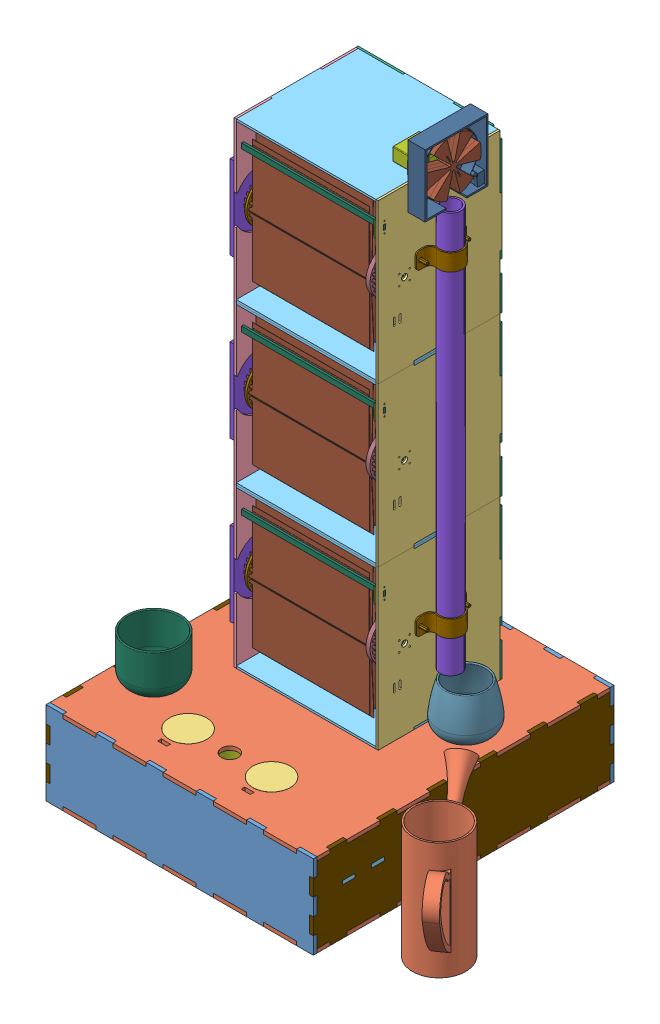
SolidWorks assembly TopLevelAssy_final, configuration Default. Lengths in mm.
Overall size (1478.61 1160.69 1655.18).
164 component instances, 34 part files, 63 mates.
Components (placement in the parent):
- Pot-1: Pot [Default] at (31.4512 127 168.0022) x (0.976936 0 0.213531) z (-0.213531 0 0.976936) size (88.9 76.2 88.9)
- WateringCan-1: WateringCan [Default] at (300.071 0 362.7314) x (-0.576518 0 -0.817085) z (0.817085 0 -0.576518) size (261.08 212.45 184)
- SingleBox-1: SingleBox [Default] at (-1041.1586 1159.5345 1655.1813) size (8.25 0 8.5)
- AllAssembly-v1-stacked-1: AllAssembly-v1-stacked [Default] at (107.7489 434.7752 58.4339) x (0 0 1) z (0 -1 0) size (239.32 247.83 744.86)
  - BasicFlipbook-1: BasicFlipbook [Default] at (-56.8677 536.304 -217.1524) size (239.32 247.83 262.26)
    - sidePanel-bearing-1: sidePanel-bearing [Default] at (77.8088 -538.0926 524.9276) size (188.59 3.17 241.3)
    - sidePanel-spindle-1: sidePanel-spindle [Default] at (77.8088 -322.1926 524.9276) size (188.59 3.17 241.3)
    - topPanel-1: topPanel [Default] at (170.5188 -428.5551 283.6276) x (0 -1 0) z (0 0 1) size (219.07 188.59 3.17)
    - topPanel-2: topPanel [Default] at (170.5188 -428.5551 521.7526) x (0 -1 0) z (0 0 1) size (219.07 188.59 3.17)
    - backPanel-1: backPanel [Default] at (77.8088 -538.0926 524.9276) x (0 1 0) z (0 0 1) size (219.07 3.17 241.3)
    - servo-1: servo [Default] at (213.1908 -290.2676 404.2776) x (1 0 0) z (0 -1 0) size (52.83 20.07 43.1)
    - sidePanel-motor-1: sidePanel-motor [Default] at (77.8088 -319.0176 524.9276) size (101.6 6.35 127)
    - FlipHubAssy_11_14_16-2: FlipHubAssy_11_14_16 [Default] at (223.2238 -424.2676 404.2776) x (0 1 0) z (0.343761 0 0.939057) size (212.25 171.9 216.35) (flexible)
      - Hub_11_16_16v1-3: Hub_11_16_16v1 [Kerf Removed] at (92.075 0 0) x (0 -0.836215 0.548402) z (1 0 0) size (67.6 67.6 3.17)
      - 4mmShaft-1: 4mmShaft [Default] at (-110.65 0 0) x (0 0.397838 0.917456) z (1 0 0) size (4 4 201.85)
      - flipcard-2: flipcard [Default] at (101.6 -15.2897 -21.654) x (-1 0 0) z (0 0.118273 0.992981) size (203.2 0.36 88.9)
      - flipcard-3: flipcard [Default] at (101.6 -20.7049 -16.8264) x (-1 0 0) z (0 0.229727 0.973255) size (203.2 0.36 88.9)
      - flipcard-4: flipcard [Default] at (101.6 -24.7798 -10.679) x (-1 0 0) z (0 0.290896 0.956755) size (203.2 0.36 88.9)
      - flipcard-5: flipcard [Default] at (101.6 -27.1726 -3.6323) x (-1 0 0) z (0 0.324243 0.945974) size (203.2 0.36 88.9)
      - flipcard-6: flipcard [Default] at (101.6 -27.6554 3.8125) x (-1 0 0) z (0 0.355007 0.934864) size (203.2 0.36 88.9)
      - flipcard-7: flipcard [Default] at (101.6 6.9617 25.991) x (-1 0 0) z (0 -0.804275 -0.594258) size (203.2 0.36 88.9)
      - flipcard-8: flipcard [Default] at (101.6 13.6608 22.8217) x (-1 0 0) z (0 -0.829103 -0.559096) size (203.2 0.36 88.9)
      - flipcard-9: flipcard [Default] at (101.6 12.4258 -23.2935) x (-1 0 0) z (0 -0.27854 0.960425) size (203.2 0.36 88.9)
      - flipcard-10: flipcard [Default] at (101.6 19.1668 18.301) x (-1 0 0) z (0 -0.912348 -0.409415) size (203.2 0.36 88.9)
      - flipcard-11: flipcard [Default] at (101.6 25.8239 6.5692) x (-1 0 0) z (0 -0.973268 0.229671) size (203.2 0.36 88.9)
      - flipcard-12: flipcard [Default] at (101.6 -7.402 26.2839) x (-1 0 0) z (0 -0.588891 -0.808212) size (203.2 0.36 88.9)
      - flipcard-13: flipcard [Default] at (101.6 23.2571 13.1974) x (-1 0 0) z (0 -0.999195 0.040112) size (203.2 0.36 88.9)
      - flipcard-14: flipcard [Default] at (101.6 -0.029 26.9321) x (-1 0 0) z (0 -0.634806 -0.772672) size (203.2 0.36 88.9)
      - flipcard-15: flipcard [Default] at (101.6 -14.3329 23.6973) x (-1 0 0) z (0 -0.524162 -0.851618) size (203.2 0.36 88.9)
      - flipcard-16: flipcard [Default] at (101.6 25.5857 -7.2828) x (-1 0 0) z (0 -0.75236 0.658752) size (203.2 0.36 88.9)
      - flipcard-17: flipcard [Default] at (101.6 -20.2143 19.2851) x (-1 0 0) z (0 -0.387069 -0.922051) size (203.2 0.36 88.9)
      - flipcard-18: flipcard [Default] at (101.6 -26.2822 11.1902) x (-1 0 0) z (0 0.343761 0.939057) size (203.2 0.36 88.9)
      - flipcard-19: flipcard [Default] at (101.6 26.6468 -0.3343) x (-1 0 0) z (0 -0.879712 0.475507) size (203.2 0.36 88.9)
      - flipcard-20: flipcard [Default] at (101.6 -25.0081 13.5575) x (-1 0 0) z (0 -0.343761 -0.939057) size (203.2 0.36 88.9)
      - flipcard-21: flipcard [Default] at (101.6 22.7931 -13.6775) x (-1 0 0) z (0 -0.570443 0.821337) size (203.2 0.36 88.9)
      - flipcard-22: flipcard [Default] at (101.6 5.6236 -25.7226) x (-1 0 0) z (0 -0.165302 0.986243) size (203.2 0.36 88.9)
      - flipcard-23: flipcard [Default] at (101.6 -1.5593 -26.2681) x (-1 0 0) z (0 -0.043757 0.999042) size (203.2 0.36 88.9)
      - flipcard-24: flipcard [Default] at (101.6 18.5239 -19.098) x (-1 0 0) z (0 -0.319136 0.947709) size (203.2 0.36 88.9)
      - flipcard-26: flipcard [Default] at (101.6 -8.628 -24.8962) x (-1 0 0) z (0 0.08016 0.996782) size (203.2 0.36 88.9)
      - CenterSupport-2: CenterSupport [After Cut Kerf Removed] at (0 3.7916 3.0025) x (1 0 0) z (0 -0.836215 0.548402) size (190.5 19.05 3.05)
      - CenterSupport-3: CenterSupport [After Cut Kerf Removed] at (0 -3.0025 3.7916) x (1 0 0) z (0 -0.548402 -0.836215) size (190.5 19.05 3.05)
      - CenterSupport-4: CenterSupport [After Cut Kerf Removed] at (0 -3.7916 -3.0025) x (1 0 0) z (0 0.836215 -0.548402) size (190.5 19.05 3.05)
      - CenterSupport-5: CenterSupport [After Cut Kerf Removed] at (0 3.0025 -3.7916) x (1 0 0) z (0 0.548402 0.836215) size (190.5 19.05 3.05)
      - Hub_11_16_16v1-thicker-3: Hub_11_16_16v1-thicker [Kerf Removed] at (-95.25 0 0) x (0 -0.548402 -0.836215) z (1 0 0) size (67.6 72.68 6.35)
      - bearingSleeve-nut-1: bearingSleeve-nut [Default] at (-109.05 0 0) x (0 -0.939057 0.343761) z (-1 0 0) size (25.4 25.4 6.95)
    - stopper-2: stopper [Default] at (255.3548 -538.0926 327.0616) x (0 1 0) z (-1 0 0) size (219.07 7.87 3.3)
    - stopperSupport-1: stopperSupport [Default] at (243.9268 -531.9176 311.1876) x (1 0 0) z (0 -1 0) size (19.3 23.87 3)
    - switchSupport-1: switchSupport [Default] at (224.5478 -534.9176 453.6616) x (1 0 0) z (0 1 0) size (19.84 9.4 12.7)
  - BasicFlipbook-2: BasicFlipbook [Default] at (-56.8677 536.304 -458.4524) size (239.32 247.83 262.26)
    - sidePanel-bearing-1: sidePanel-bearing [Default] at (77.8088 -538.0926 524.9276) size (188.59 3.17 241.3)
    - sidePanel-spindle-1: sidePanel-spindle [Default] at (77.8088 -322.1926 524.9276) size (188.59 3.17 241.3)
    - topPanel-1: topPanel [Default] at (170.5188 -428.5551 283.6276) x (0 -1 0) z (0 0 1) size (219.07 188.59 3.17)
    - topPanel-2: topPanel [Default] at (170.5188 -428.5551 521.7526) x (0 -1 0) z (0 0 1) size (219.07 188.59 3.17)
    - backPanel-1: backPanel [Default] at (77.8088 -538.0926 524.9276) x (0 1 0) z (0 0 1) size (219.07 3.17 241.3)
    - servo-1: servo [Default] at (213.1908 -290.2676 404.2776) x (1 0 0) z (0 -1 0) size (52.83 20.07 43.1)
    - sidePanel-motor-1: sidePanel-motor [Default] at (77.8088 -319.0176 524.9276) size (101.6 6.35 127)
    - FlipHubAssy_11_14_16-2: FlipHubAssy_11_14_16 [Default] at (223.2238 -424.2676 404.2776) x (0 1 0) z (0.343761 0 0.939057) size (212.25 171.9 216.35) (flexible)
      - Hub_11_16_16v1-3: Hub_11_16_16v1 [Kerf Removed] at (92.075 0 0) x (0 -0.836215 0.548402) z (1 0 0) size (67.6 67.6 3.17)
      - 4mmShaft-1: 4mmShaft [Default] at (-110.65 0 0) x (0 0.397838 0.917456) z (1 0 0) size (4 4 201.85)
      - flipcard-2: flipcard [Default] at (101.6 -15.2897 -21.654) x (-1 0 0) z (0 0.118273 0.992981) size (203.2 0.36 88.9)
      - flipcard-3: flipcard [Default] at (101.6 -20.7049 -16.8264) x (-1 0 0) z (0 0.229727 0.973255) size (203.2 0.36 88.9)
      - flipcard-4: flipcard [Default] at (101.6 -24.7798 -10.679) x (-1 0 0) z (0 0.290896 0.956755) size (203.2 0.36 88.9)
      - flipcard-5: flipcard [Default] at (101.6 -27.1726 -3.6323) x (-1 0 0) z (0 0.324243 0.945974) size (203.2 0.36 88.9)
      - flipcard-6: flipcard [Default] at (101.6 -27.6554 3.8125) x (-1 0 0) z (0 0.355007 0.934864) size (203.2 0.36 88.9)
      - flipcard-7: flipcard [Default] at (101.6 6.9617 25.991) x (-1 0 0) z (0 -0.804275 -0.594258) size (203.2 0.36 88.9)
      - flipcard-8: flipcard [Default] at (101.6 13.6608 22.8217) x (-1 0 0) z (0 -0.829103 -0.559096) size (203.2 0.36 88.9)
      - flipcard-9: flipcard [Default] at (101.6 12.4258 -23.2935) x (-1 0 0) z (0 -0.27854 0.960425) size (203.2 0.36 88.9)
      - flipcard-10: flipcard [Default] at (101.6 19.1668 18.301) x (-1 0 0) z (0 -0.912348 -0.409415) size (203.2 0.36 88.9)
      - flipcard-11: flipcard [Default] at (101.6 25.8239 6.5692) x (-1 0 0) z (0 -0.973268 0.229671) size (203.2 0.36 88.9)
      - flipcard-12: flipcard [Default] at (101.6 -7.402 26.2839) x (-1 0 0) z (0 -0.588891 -0.808212) size (203.2 0.36 88.9)
      - flipcard-13: flipcard [Default] at (101.6 23.2571 13.1974) x (-1 0 0) z (0 -0.999195 0.040112) size (203.2 0.36 88.9)
      - flipcard-14: flipcard [Default] at (101.6 -0.029 26.9321) x (-1 0 0) z (0 -0.634806 -0.772672) size (203.2 0.36 88.9)
      - flipcard-15: flipcard [Default] at (101.6 -14.3329 23.6973) x (-1 0 0) z (0 -0.524162 -0.851618) size (203.2 0.36 88.9)
      - flipcard-16: flipcard [Default] at (101.6 25.5857 -7.2828) x (-1 0 0) z (0 -0.75236 0.658752) size (203.2 0.36 88.9)
      - flipcard-17: flipcard [Default] at (101.6 -20.2143 19.2851) x (-1 0 0) z (0 -0.387069 -0.922051) size (203.2 0.36 88.9)
      - flipcard-18: flipcard [Default] at (101.6 -26.2822 11.1902) x (-1 0 0) z (0 0.343761 0.939057) size (203.2 0.36 88.9)
      - flipcard-19: flipcard [Default] at (101.6 26.6468 -0.3343) x (-1 0 0) z (0 -0.879712 0.475507) size (203.2 0.36 88.9)
      - flipcard-20: flipcard [Default] at (101.6 -25.0081 13.5575) x (-1 0 0) z (0 -0.343761 -0.939057) size (203.2 0.36 88.9)
      - flipcard-21: flipcard [Default] at (101.6 22.7931 -13.6775) x (-1 0 0) z (0 -0.570443 0.821337) size (203.2 0.36 88.9)
      - flipcard-22: flipcard [Default] at (101.6 5.6236 -25.7226) x (-1 0 0) z (0 -0.165302 0.986243) size (203.2 0.36 88.9)
      - flipcard-23: flipcard [Default] at (101.6 -1.5593 -26.2681) x (-1 0 0) z (0 -0.043757 0.999042) size (203.2 0.36 88.9)
      - flipcard-24: flipcard [Default] at (101.6 18.5239 -19.098) x (-1 0 0) z (0 -0.319136 0.947709) size (203.2 0.36 88.9)
      - flipcard-26: flipcard [Default] at (101.6 -8.628 -24.8962) x (-1 0 0) z (0 0.08016 0.996782) size (203.2 0.36 88.9)
      - CenterSupport-2: CenterSupport [After Cut Kerf Removed] at (0 3.7916 3.0025) x (1 0 0) z (0 -0.836215 0.548402) size (190.5 19.05 3.05)
      - CenterSupport-3: CenterSupport [After Cut Kerf Removed] at (0 -3.0025 3.7916) x (1 0 0) z (0 -0.548402 -0.836215) size (190.5 19.05 3.05)
      - CenterSupport-4: CenterSupport [After Cut Kerf Removed] at (0 -3.7916 -3.0025) x (1 0 0) z (0 0.836215 -0.548402) size (190.5 19.05 3.05)
      - CenterSupport-5: CenterSupport [After Cut Kerf Removed] at (0 3.0025 -3.7916) x (1 0 0) z (0 0.548402 0.836215) size (190.5 19.05 3.05)
      - Hub_11_16_16v1-thicker-3: Hub_11_16_16v1-thicker [Kerf Removed] at (-95.25 0 0) x (0 -0.548402 -0.836215) z (1 0 0) size (67.6 72.68 6.35)
      - bearingSleeve-nut-1: bearingSleeve-nut [Default] at (-109.05 0 0) x (0 -0.939057 0.343761) z (-1 0 0) size (25.4 25.4 6.95)
    - stopper-2: stopper [Default] at (255.3548 -538.0926 327.0616) x (0 1 0) z (-1 0 0) size (219.07 7.87 3.3)
    - stopperSupport-1: stopperSupport [Default] at (243.9268 -531.9176 311.1876) x (1 0 0) z (0 -1 0) size (19.3 23.87 3)
    - switchSupport-1: switchSupport [Default] at (224.5478 -534.9176 453.6616) x (1 0 0) z (0 1 0) size (19.84 9.4 12.7)
  - BasicFlipbook-3: BasicFlipbook [Default] at (-56.8677 536.304 -699.7524) size (239.32 247.83 262.26)
    - sidePanel-bearing-1: sidePanel-bearing [Default] at (77.8088 -538.0926 524.9276) size (188.59 3.17 241.3)
    - sidePanel-spindle-1: sidePanel-spindle [Default] at (77.8088 -322.1926 524.9276) size (188.59 3.17 241.3)
    - topPanel-1: topPanel [Default] at (170.5188 -428.5551 283.6276) x (0 -1 0) z (0 0 1) size (219.07 188.59 3.17)
    - topPanel-2: topPanel [Default] at (170.5188 -428.5551 521.7526) x (0 -1 0) z (0 0 1) size (219.07 188.59 3.17)
    - backPanel-1: backPanel [Default] at (77.8088 -538.0926 524.9276) x (0 1 0) z (0 0 1) size (219.07 3.17 241.3)
    - servo-1: servo [Default] at (213.1908 -290.2676 404.2776) x (1 0 0) z (0 -1 0) size (52.83 20.07 43.1)
    - sidePanel-motor-1: sidePanel-motor [Default] at (77.8088 -319.0176 524.9276) size (101.6 6.35 127)
    - FlipHubAssy_11_14_16-2: FlipHubAssy_11_14_16 [Default] at (223.2238 -424.2676 404.2776) x (0 1 0) z (0.343761 0 0.939057) size (212.25 171.9 216.35) (flexible)
      - Hub_11_16_16v1-3: Hub_11_16_16v1 [Kerf Removed] at (92.075 0 0) x (0 -0.836215 0.548402) z (1 0 0) size (67.6 67.6 3.17)
      - 4mmShaft-1: 4mmShaft [Default] at (-110.65 0 0) x (0 0.397838 0.917456) z (1 0 0) size (4 4 201.85)
      - flipcard-2: flipcard [Default] at (101.6 -15.2897 -21.654) x (-1 0 0) z (0 0.118273 0.992981) size (203.2 0.36 88.9)
      - flipcard-3: flipcard [Default] at (101.6 -20.7049 -16.8264) x (-1 0 0) z (0 0.229727 0.973255) size (203.2 0.36 88.9)
      - flipcard-4: flipcard [Default] at (101.6 -24.7798 -10.679) x (-1 0 0) z (0 0.290896 0.956755) size (203.2 0.36 88.9)
      - flipcard-5: flipcard [Default] at (101.6 -27.1726 -3.6323) x (-1 0 0) z (0 0.324243 0.945974) size (203.2 0.36 88.9)
      - flipcard-6: flipcard [Default] at (101.6 -27.6554 3.8125) x (-1 0 0) z (0 0.355007 0.934864) size (203.2 0.36 88.9)
      - flipcard-7: flipcard [Default] at (101.6 6.9617 25.991) x (-1 0 0) z (0 -0.804275 -0.594258) size (203.2 0.36 88.9)
      - flipcard-8: flipcard [Default] at (101.6 13.6608 22.8217) x (-1 0 0) z (0 -0.829103 -0.559096) size (203.2 0.36 88.9)
      - flipcard-9: flipcard [Default] at (101.6 12.4258 -23.2935) x (-1 0 0) z (0 -0.27854 0.960425) size (203.2 0.36 88.9)
      - flipcard-10: flipcard [Default] at (101.6 19.1668 18.301) x (-1 0 0) z (0 -0.912348 -0.409415) size (203.2 0.36 88.9)
      - flipcard-11: flipcard [Default] at (101.6 25.8239 6.5692) x (-1 0 0) z (0 -0.973268 0.229671) size (203.2 0.36 88.9)
      - flipcard-12: flipcard [Default] at (101.6 -7.402 26.2839) x (-1 0 0) z (0 -0.588891 -0.808212) size (203.2 0.36 88.9)
      - flipcard-13: flipcard [Default] at (101.6 23.2571 13.1974) x (-1 0 0) z (0 -0.999195 0.040112) size (203.2 0.36 88.9)
      - flipcard-14: flipcard [Default] at (101.6 -0.029 26.9321) x (-1 0 0) z (0 -0.634806 -0.772672) size (203.2 0.36 88.9)
      - flipcard-15: flipcard [Default] at (101.6 -14.3329 23.6973) x (-1 0 0) z (0 -0.524162 -0.851618) size (203.2 0.36 88.9)
      - flipcard-16: flipcard [Default] at (101.6 25.5857 -7.2828) x (-1 0 0) z (0 -0.75236 0.658752) size (203.2 0.36 88.9)
      - flipcard-17: flipcard [Default] at (101.6 -20.2143 19.2851) x (-1 0 0) z (0 -0.387069 -0.922051) size (203.2 0.36 88.9)
      - flipcard-18: flipcard [Default] at (101.6 -26.2822 11.1902) x (-1 0 0) z (0 0.343761 0.939057) size (203.2 0.36 88.9)
      - flipcard-19: flipcard [Default] at (101.6 26.6468 -0.3343) x (-1 0 0) z (0 -0.879712 0.475507) size (203.2 0.36 88.9)
      - flipcard-20: flipcard [Default] at (101.6 -25.0081 13.5575) x (-1 0 0) z (0 -0.343761 -0.939057) size (203.2 0.36 88.9)
      - flipcard-21: flipcard [Default] at (101.6 22.7931 -13.6775) x (-1 0 0) z (0 -0.570443 0.821337) size (203.2 0.36 88.9)
      - flipcard-22: flipcard [Default] at (101.6 5.6236 -25.7226) x (-1 0 0) z (0 -0.165302 0.986243) size (203.2 0.36 88.9)
      - flipcard-23: flipcard [Default] at (101.6 -1.5593 -26.2681) x (-1 0 0) z (0 -0.043757 0.999042) size (203.2 0.36 88.9)
      - flipcard-24: flipcard [Default] at (101.6 18.5239 -19.098) x (-1 0 0) z (0 -0.319136 0.947709) size (203.2 0.36 88.9)
      - flipcard-26: flipcard [Default] at (101.6 -8.628 -24.8962) x (-1 0 0) z (0 0.08016 0.996782) size (203.2 0.36 88.9)
      - CenterSupport-2: CenterSupport [After Cut Kerf Removed] at (0 3.7916 3.0025) x (1 0 0) z (0 -0.836215 0.548402) size (190.5 19.05 3.05)
      - CenterSupport-3: CenterSupport [After Cut Kerf Removed] at (0 -3.0025 3.7916) x (1 0 0) z (0 -0.548402 -0.836215) size (190.5 19.05 3.05)
      - CenterSupport-4: CenterSupport [After Cut Kerf Removed] at (0 -3.7916 -3.0025) x (1 0 0) z (0 0.836215 -0.548402) size (190.5 19.05 3.05)
      - CenterSupport-5: CenterSupport [After Cut Kerf Removed] at (0 3.0025 -3.7916) x (1 0 0) z (0 0.548402 0.836215) size (190.5 19.05 3.05)
      - Hub_11_16_16v1-thicker-3: Hub_11_16_16v1-thicker [Kerf Removed] at (-95.25 0 0) x (0 -0.548402 -0.836215) z (1 0 0) size (67.6 72.68 6.35)
      - bearingSleeve-nut-1: bearingSleeve-nut [Default] at (-109.05 0 0) x (0 -0.939057 0.343761) z (-1 0 0) size (25.4 25.4 6.95)
    - stopper-2: stopper [Default] at (255.3548 -538.0926 327.0616) x (0 1 0) z (-1 0 0) size (219.07 7.87 3.3)
    - stopperSupport-1: stopperSupport [Default] at (243.9268 -531.9176 311.1876) x (1 0 0) z (0 -1 0) size (19.3 23.87 3)
    - switchSupport-1: switchSupport [Default] at (224.5478 -534.9176 453.6616) x (1 0 0) z (0 1 0) size (19.84 9.4 12.7)
- Box_LeftRight-1: Box_LeftRight [Default] at (203.2 63.5 228.6) x (0 0 1) z (-1 0 0) size (457.2 127 5.71)
- Box_LeftRight-2: Box_LeftRight [Left] at (-197.485 63.5 228.6) x (0 0 1) z (-1 0 0) size (457.2 127 5.71)
- Box_FrontBack-2: Box_FrontBack [Back] at (0 63.5 0) size (406.4 127 5.71)
- Box_TopBottom-1: Box_TopBottom [Simple Bottom] at (0 0 228.6) x (1 0 0) z (0 1 0) size (406.4 457.2 5.71)
- Box_FrontBack-1: Box_FrontBack [Front] at (0 63.5 451.485) size (406.4 127 5.71)
- Box_TopBottom-2: Box_TopBottom [Simple Top] at (0 121.285 228.6) x (1 0 0) z (0 1 0) size (406.4 457.2 5.71)
- Box_FrostedHand-1: Box_FrostedHand [Default] at (-63.5 121.3358 381) x (1 0 0) z (0 1 0) size (56.64 56.64 5.71)
- Box_FrostedHand-2: Box_FrostedHand [Default] at (63.5 121.412 381) x (1 0 0) z (0 1 0) size (56.64 56.64 5.71)
- SeedDoor-1: SeedDoor [Default] at (-206.375 26.4984 358.3219) x (0 -0.092883 -0.995677) z (1 0 0) size (50.8 50.8 3.17)
- Box_LED_Sensor Mount-1: Box_LED_Sensor Mount [Default] at (0 70.485 381) x (1 0 0) z (0 1 0) size (406.4 63.5 5.71)
- PowerSupply-1: PowerSupply [Default] at (-124.46 5.715 202.565) x (0 0 -1) z (1 0 0) size (203.2 101.6 133.35)
- SeedLEDShroud-1: SeedLEDShroud [Default] at (63.5 120.65 381) x (1 0 0) z (0 -1 0) size (50.8 50.8 44.45)
- SeedLEDShroud-2: SeedLEDShroud [Default] at (-63.5 120.65 381) x (1 0 0) z (0 -1 0) size (50.8 50.8 44.45)
- SeedLEDShroud-3: SeedLEDShroud [Default] at (0 120.65 381) x (1 0 0) z (0 -1 0) size (50.8 50.8 44.45)
- SeedTube-1: SeedTube [Default] at (125.4125 806.45 170.4975) x (-0.559231 0 -0.829012) z (0 -1 0) size (31.75 31.75 609.6)
- SeedTubeBracket-1: SeedTubeBracket [Default] at (109.5375 247.65 170.4975) x (0 0 1) z (-1 0 0) size (76.2 25.4 33.78)
- SeedTubeBracket-2: SeedTubeBracket [Default] at (109.5375 730.25 170.4975) x (0 0 1) z (-1 0 0) size (76.2 25.4 33.78)
- FruitDispenseAssm-1: FruitDispenseAssm [Default] at (109.5375 860.933 172.085) x (0 0 -1) z (1 0 0) size (95.25 95.25 66.48)
  - servo-1: servo [Default] at (-10.033 0 -40.1) size (52.83 20.07 43.1)
  - FruitDispenseDrum-1: FruitDispenseDrum [Default] x (-1 0 0) z (0 0 -1) size (95.25 95.25 26.38)
- FruitPaddleWheel-2: FruitPaddleWheel [Default] at (131.5875 860.933 172.085) x (0 1 0) z (0 0 1) size (81.32 19.05 83.82)
  - fruitMotorSpindle1-1: fruitMotorSpindle1 [Default] at origin size (81.32 6.35 83.82)
  - fruitMotorSpindle1-2: fruitMotorSpindle1 [Default] at (0 6.35 0) size (81.32 6.35 83.82)
  - fruitMotorSpindle1-3: fruitMotorSpindle1 [Default] at (0 12.7 0) size (81.32 6.35 83.82)
- SeedRamp-1: SeedRamp [Default] at (-197.485 5.715 339.725) x (0 0 1) z (-1 0 0) size (111.76 63.5 254)
- CircuitLayout-1: CircuitLayout [Default] at (-31.115 5.715 393.065) x (1 0 0) z (0 1 0) size (317.5 381 50.8)
- FruitGlass-1: FruitGlass [Default] at (150.8125 127 172.7726) x (-0.420832 0 -0.907138) z (0.907138 0 -0.420832) size (82.55 69.47 82.55)
- SeedGlass-2: SeedGlass [Default] at (-149.8177 127 346.9329) size (82.55 69.9 82.55)
Mates (geometry in assembly coordinates):
- Coincident9: coincident anti-aligned: plane of Box_TopBottom-2 through (0 127 228.6) normal (0 1 0); plane of Pot-1 through (31.4512 127 168.0022) normal (0 -1 0)
- Coincident10: coincident aligned: plane of Box_TopBottom-1 through (0 0 228.6) normal (0 -1 0); plane of WateringCan-1 through (300.071 0 362.7314) normal (0 -1 0)
- Coincident12: coincident: moEndPointRef_w of AllAssembly-v1-stacked-1/BasicFlipbook-1/topPanel-2; plane of assembly
- Coincident14: coincident aligned: plane of Box_TopBottom-1 through (-203.2 5.715 457.2) normal (-1 0 0); plane of Box_TopBottom-2 through (-203.2 127 457.2) normal (-1 0 0)
- Coincident15: coincident aligned: plane of Box_TopBottom-1 through (-203.2 5.715 457.2) normal (0 0 1); plane of Box_TopBottom-2 through (-203.2 127 457.2) normal (0 0 1)
- Coincident18: coincident aligned: plane of Box_TopBottom-1 through (-203.2 5.715 457.2) normal (-1 0 0); plane of Box_LeftRight-2 through (-203.2 63.5 228.6) normal (-1 0 0)
- Coincident21: coincident aligned: plane of Box_TopBottom-2 through (0 127 228.6) normal (0 1 0); plane of Box_LeftRight-1 through (197.485 127 0) normal (0 1 0)
- Coincident22: coincident aligned: plane of Box_TopBottom-2 through (-203.2 127 457.2) normal (0 0 1); plane of Box_FrontBack-1 through (0 63.5 457.2) normal (0 0 1)
- Coincident23: coincident aligned: plane of Box_TopBottom-2 through (-203.2 127 457.2) normal (-1 0 0); plane of Box_FrontBack-1 through (-203.2 0 457.2) normal (-1 0 0)
- Coincident24: coincident aligned: plane of Box_TopBottom-2 through (0 127 228.6) normal (0 1 0); plane of Box_FrontBack-1 through (-203.2 127 457.2) normal (0 1 0)
- Coincident26: coincident aligned: plane of Box_TopBottom-2 through (203.2 127 457.2) normal (1 0 0); plane of Box_FrontBack-2 through (203.2 0 5.715) normal (1 0 0)
- Coincident27: coincident aligned: plane of Box_TopBottom-2 through (0 127 228.6) normal (0 1 0); plane of Box_FrontBack-2 through (-203.2 127 5.715) normal (0 1 0)
- Coincident28: coincident anti-aligned: plane of Box_TopBottom-1 through (0 0 228.6) normal (0 -1 0); plane of assembly through (0 0 0) normal (0 1 0)
- Coincident29: coincident aligned: plane of Box_TopBottom-2; plane of assembly through (0 0 0) normal (1 0 0)
- Coincident30: coincident anti-aligned: plane of Box_TopBottom-1 through (-203.2 5.715 0) normal (0 0 -1); plane of assembly through (0 0 0) normal (0 0 1)
- Coincident58: coincident aligned: plane of Box_LeftRight-2 through (-203.2 127 0) normal (0 1 0); plane of Box_TopBottom-2 through (0 127 228.6) normal (0 1 0)
- Coincident60: coincident aligned: plane of Box_LeftRight-2 through (-203.2 0 457.2) normal (0 0 1); plane of Box_FrontBack-1 through (0 63.5 457.2) normal (0 0 1)
- Distance2: distance = 0.0508 mm aligned: plane of Box_FrostedHand-1 through (-63.5 127.0508 381) normal (0 1 0); plane of Box_TopBottom-2 through (0 127 228.6) normal (0 1 0)
- Distance3: distance = 0.127 mm aligned: plane of Box_FrostedHand-2 through (63.5 127.127 381) normal (0 1 0); plane of Box_TopBottom-2 through (0 127 228.6) normal (0 1 0)
- Concentric3: concentric aligned: cylinder of Box_TopBottom-2 through (-63.5 127 381) axis (0 -1 0) radius 28.321; cylinder of Box_FrostedHand-1 through (-63.5 127.0508 381) axis (0 -1 0) radius 28.321
- Concentric4: concentric aligned: cylinder of Box_TopBottom-2 through (63.5 127 381) axis (0 -1 0) radius 28.321; cylinder of Box_FrostedHand-2 through (63.5 127.127 381) axis (0 -1 0) radius 28.321
- Coincident61: coincident anti-aligned: plane of AllAssembly-v1-stacked-1/BasicFlipbook-1/topPanel-2 through (0 127 172.085) normal (0 -1 0); plane of Box_TopBottom-2 through (0 127 228.6) normal (0 1 0)
- Coincident62: coincident aligned: plane of Box_LeftRight-1 through (203.2 63.5 228.6) normal (1 0 0); plane of Box_TopBottom-2 through (203.2 127 457.2) normal (1 0 0)
- Coincident63: coincident aligned: plane of Box_LeftRight-1 through (197.485 0 457.2) normal (0 0 1); plane of Box_TopBottom-2 through (-203.2 127 457.2) normal (0 0 1)
- Coincident64: coincident aligned: plane of Box_FrontBack-2 through (0 63.5 0) normal (0 0 -1); plane of Box_TopBottom-2 through (-203.2 127 0) normal (0 0 -1)
- Coincident65: coincident anti-aligned: plane of Box_LeftRight-2 through (-197.485 76.2 349.25) normal (0 -1 0); plane of Box_LED_Sensor Mount-1 through (0 76.2 381) normal (0 1 0)
- Coincident66: coincident anti-aligned: plane of Box_LeftRight-2 through (-197.485 76.2 349.25) normal (0 0 1); plane of Box_LED_Sensor Mount-1 through (-203.2 76.2 349.25) normal (0 0 -1)
- Coincident67: coincident aligned: plane of Box_LeftRight-2 through (-203.2 63.5 228.6) normal (-1 0 0); plane of Box_LED_Sensor Mount-1 through (-203.2 76.2 412.75) normal (-1 0 0)
- Coincident68: coincident anti-aligned: plane of Box_TopBottom-1 through (0 5.715 228.6) normal (0 1 0); plane of PowerSupply-1 through (-124.46 5.715 202.565) normal (0 -1 0)
- Distance4: distance = 6.35 mm anti-aligned: plane of PowerSupply-1 through (-191.135 107.315 304.165) normal (-1 0 0); plane of Box_LeftRight-2 through (-197.485 63.5 228.6) normal (1 0 0)
- Coincident70: coincident aligned: plane of Box_TopBottom-1 through (0 0 228.6) normal (0 -1 0); plane of Box_FrontBack-1 through (-203.2 0 457.2) normal (0 -1 0)
- Distance5: distance = 95.25 mm aligned: plane of PowerSupply-1 through (-57.785 107.315 100.965) normal (0 0 -1); plane of Box_TopBottom-1 through (-177.8 5.715 5.715) normal (0 0 -1)
- Coincident78: coincident anti-aligned: plane of Box_LED_Sensor Mount-1 through (0 76.2 381) normal (0 1 0); plane of SeedLEDShroud-1 through (63.5 76.2 381) normal (0 -1 0)
- Concentric5: concentric aligned: circle of Box_LED_Sensor Mount-1; cylinder of SeedLEDShroud-1 through (63.5 76.2 381) axis (0 1 0) radius 25.4
- Coincident79: coincident anti-aligned: plane of Box_LED_Sensor Mount-1 through (0 76.2 381) normal (0 1 0); plane of SeedLEDShroud-2 through (-63.5 76.2 381) normal (0 -1 0)
- Concentric6: concentric anti-aligned: cylinder of Box_LED_Sensor Mount-1 through (-63.5 76.2 381) axis (0 -1 0) radius 2.54; cylinder of SeedLEDShroud-2 through (-63.5 76.2 381) axis (0 1 0) radius 21.59
- Concentric7: concentric anti-aligned: cylinder of Box_LED_Sensor Mount-1 through (0 76.2 381) axis (0 -1 0) radius 12.7; cylinder of SeedLEDShroud-3 through (0 76.2 381) axis (0 1 0) radius 21.59
- Coincident80: coincident anti-aligned: plane of Box_LED_Sensor Mount-1 through (0 76.2 381) normal (0 1 0); plane of SeedLEDShroud-3 through (0 76.2 381) normal (0 -1 0)
- Concentric8: concentric anti-aligned: cylinder of SeedTube-1 through (125.4125 196.85 170.4975) axis (0 1 0) radius 15.875; cylinder of SeedTubeBracket-1 through (125.4125 273.05 170.4975) axis (0 -1 0) radius 15.875
- Concentric9: concentric anti-aligned: cylinder of SeedTube-1 through (125.4125 196.85 170.4975) axis (0 1 0) radius 15.875; cylinder of SeedTubeBracket-2 through (125.4125 755.65 170.4975) axis (0 -1 0) radius 15.875
- Distance6: distance = 50.8 mm aligned: plane of SeedTubeBracket-1 through (119.6975 247.65 195.8975) normal (0 -1 0); plane of SeedTube-1 through (125.4125 196.85 170.4975) normal (0 -1 0)
- Distance7: distance = 50.8 mm aligned: plane of SeedTube-1 through (125.4125 806.45 170.4975) normal (0 1 0); plane of SeedTubeBracket-2 through (119.6975 755.65 195.8975) normal (0 1 0)
- Coincident83: coincident anti-aligned: plane of AllAssembly-v1-stacked-1/BasicFlipbook-3/sidePanel-bearing-1 through (109.5375 609.6 79.375) normal (1 0 0); plane of SeedTubeBracket-2 through (109.5375 755.65 145.0975) normal (-1 0 0)
- Distance9: distance = 76.2 mm aligned: plane of AllAssembly-v1-stacked-1/BasicFlipbook-1/backPanel-1 through (109.5375 127 76.2) normal (0 0 -1); plane of Box_TopBottom-2 through (-203.2 127 0) normal (0 0 -1)
- Coincident85: coincident anti-aligned: plane of Box_TopBottom-2 through (0 127 228.6) normal (0 1 0); plane of FruitGlass-1 through (150.8125 127 172.7726) normal (0 -1 0)
- Coincident86: coincident anti-aligned: plane of AllAssembly-v1-stacked-1/BasicFlipbook-3/sidePanel-bearing-1 through (109.5375 609.6 79.375) normal (1 0 0); plane of SeedTubeBracket-1 through (109.5375 273.05 145.0975) normal (-1 0 0)
- Symmetric1: symmetric aligned: plane of AllAssembly-v1-stacked-1/BasicFlipbook-1/sidePanel-bearing-1 through (106.3625 127 264.795) normal (0 0 1); plane of AllAssembly-v1-stacked-1/BasicFlipbook-1/backPanel-1 through (109.5375 127 76.2) normal (0 0 -1); plane of SeedTubeBracket-1 through (109.5375 247.65 170.4975) normal (0 0 1)
- Distance10: distance = 44.45 mm aligned: plane of AllAssembly-v1-stacked-1/BasicFlipbook-3/topPanel-1 through (0 850.9 172.085) normal (0 1 0); plane of SeedTube-1 through (125.4125 806.45 170.4975) normal (0 1 0)
- Tangent1: tangent: plane of AllAssembly-v1-stacked-1/BasicFlipbook-1/sidePanel-bearing-1 through (109.5375 127 79.375) normal (1 0 0); torus of FruitGlass-1
- Coincident88: coincident anti-aligned: plane of Box_TopBottom-1 through (0 5.715 228.6) normal (0 1 0); plane of CircuitLayout-1 through (-31.115 5.715 393.065) normal (0 -1 0)
- Coincident89: coincident anti-aligned: plane of Box_LeftRight-1 through (197.485 63.5 228.6) normal (-1 0 0); plane of CircuitLayout-1 through (197.485 8.255 393.065) normal (1 0 0)
- Distance12: distance = 6.35 mm aligned: plane of CircuitLayout-1 through (-31.115 8.255 12.065) normal (0 0 -1); plane of Box_LeftRight-1 through (197.485 76.2 5.715) normal (0 0 -1)
- Coincident90: coincident anti-aligned: plane of AllAssembly-v1-stacked-1/BasicFlipbook-3/sidePanel-bearing-1 through (109.5375 609.6 79.375) normal (1 0 0); plane of FruitDispenseAssm-1/FruitDispenseDrum-1 through (109.5375 860.933 172.085) normal (-1 0 0)
- Coincident91: coincident anti-aligned: plane of AllAssembly-v1-stacked-1/BasicFlipbook-3/topPanel-1 through (0 850.9 172.085) normal (0 1 0); plane of FruitDispenseAssm-1/servo-1 through (107.5375 850.9 202.184) normal (0 -1 0)
- Coincident92: coincident: moEndPointRef_w of AllAssembly-v1-stacked-1/BasicFlipbook-3/topPanel-1; plane of FruitDispenseAssm-1 through (109.5375 860.933 172.085) normal (0 0 -1)
- Coincident93: coincident anti-aligned: plane of Box_TopBottom-2 through (0 127 228.6) normal (0 1 0); plane of SeedGlass-2 through (-149.8177 127 346.9329) normal (0 -1 0)
- Coincident94: coincident anti-aligned: plane of Box_FrontBack-1 through (0 63.5 451.485) normal (0 0 -1); plane of SeedRamp-1 through (-197.485 69.215 451.485) normal (0 0 1)
- Coincident95: coincident aligned: plane of Box_TopBottom-1 through (-197.485 5.715 406.4) normal (-1 0 0); plane of SeedRamp-1 through (-197.485 69.215 339.725) normal (-1 0 0)
- Coincident96: coincident anti-aligned: plane of Box_TopBottom-1 through (0 5.715 228.6) normal (0 1 0); plane of SeedRamp-1 through (-197.485 5.715 339.725) normal (0 -1 0)
- Concentric10: concentric anti-aligned: cylinder of Box_LeftRight-2 through (-203.2 45.466 356.5525) axis (1 0 0) radius 1.905; cylinder of SeedDoor-1 through (-203.2 45.466 356.5525) axis (-1 0 0) radius 1.905
- Coincident97: coincident anti-aligned: plane of Box_LeftRight-2 through (-203.2 63.5 228.6) normal (-1 0 0); plane of SeedDoor-1 through (-203.2 26.4984 358.3219) normal (1 0 0)
- Coincident99: coincident anti-aligned: plane of FruitDispenseAssm-1/servo-1 through (112.5375 860.933 172.085) normal (1 0 0); plane of FruitPaddleWheel-2/fruitMotorSpindle1-3 through (112.5375 860.933 172.085) normal (-1 0 0)
- Concentric12: concentric anti-aligned: cylinder of FruitDispenseAssm-1/servo-1 through (112.5375 860.933 172.085) axis (-1 0 0) radius 3.5; cylinder of FruitPaddleWheel-2/fruitMotorSpindle1-2 through (118.8875 860.933 172.085) axis (1 0 0) radius 41.91
